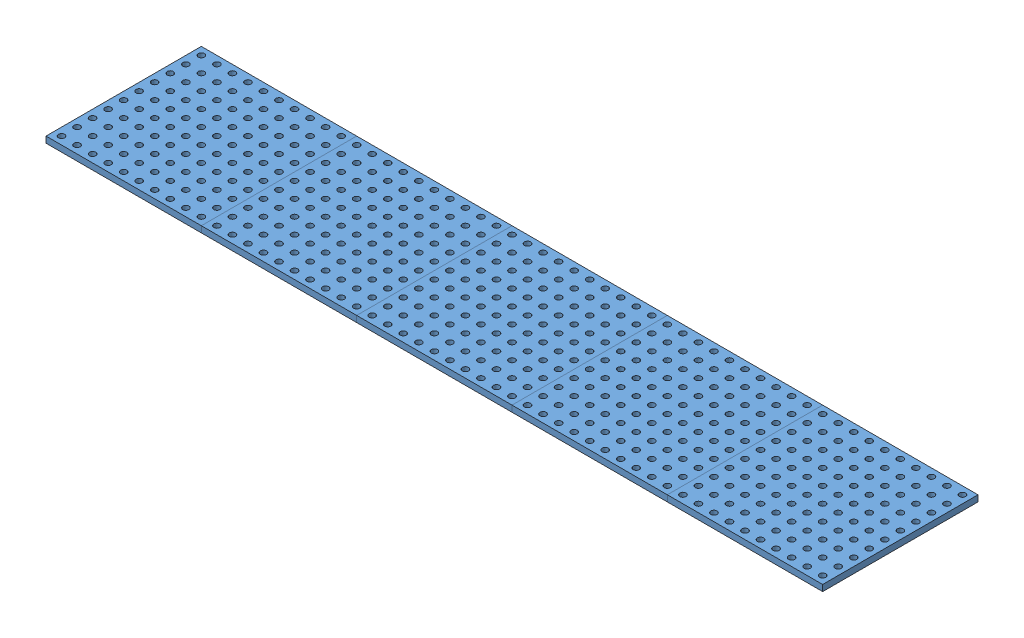
SolidWorks assembly Montagem_Base_Furada, configuration Valor predeterminado. Lengths in mm.
Overall size (2500 20 500).
5 component instances, 1 part files, 0 mates.
Components (placement in the parent):
- Base_Furada-1: Base_Furada [Valor predeterminado] at origin size (500 20 500)
- Base_Furada-4: Base_Furada [Valor predeterminado] at (500 0 0) size (500 20 500)
- Base_Furada-7: Base_Furada [Valor predeterminado] at (1000 0 0) size (500 20 500)
- Base_Furada-10: Base_Furada [Valor predeterminado] at (1500 0 0) size (500 20 500)
- Base_Furada-13: Base_Furada [Valor predeterminado] at (2000 0 0) size (500 20 500)
